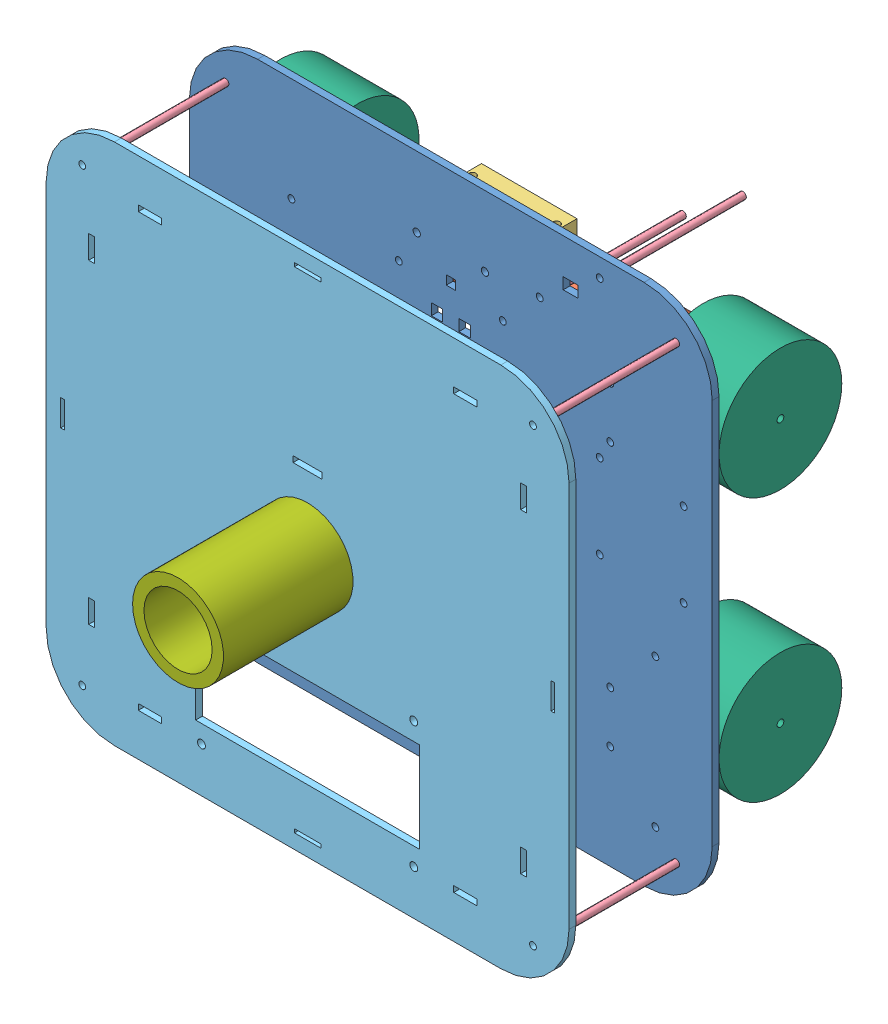
SolidWorks assembly Ensamblaje3.0, configuration Predeterminado. Lengths in mm.
Overall size (230 230 183).
20 component instances, 7 part files, 35 mates.
Components (placement in the parent):
- Basemenor 4.1-1: Basemenor 4.1 [Predeterminado] at (0.6616 -5.6238 228.5) size (230 230 3)
- Portamotores 3.1-1: Portamotores 3.1 [Predeterminado] at (-72.8434 52.3762 227.25) x (0 1 0) z (1 0 0) size (30 47 56.5)
- Portamotores 3.1-2: Portamotores 3.1 [Predeterminado] at (74.1666 -63.6238 227.25) x (0 -1 0) z (-1 0 0) size (30 47 56.5)
- Portamotores 3.1-3: Portamotores 3.1 [Predeterminado] at (74.1666 52.3762 227.25) x (0 -1 0) z (-1 0 0) size (30 47 56.5)
- Portamotores 3.1-4: Portamotores 3.1 [Predeterminado] at (-72.8434 -63.6238 227.25) x (0 1 0) z (1 0 0) size (30 47 56.5)
- Porta_sharp_1.0-1: Porta_sharp_1.0 [Predeterminado] at (-14.3384 78.3762 227.25) x (1 0 0) z (0 0 -1) size (42 12.16 31.5)
- Porta_sharp_1.0-2: Porta_sharp_1.0 [Predeterminado] at (49.6616 9.3762 227.25) x (0 -1 0) z (0 0 -1) size (42 12.16 31.5)
- Porta_sharp_1.0-3: Porta_sharp_1.0 [Predeterminado] at (-48.3384 -20.6238 227.25) x (0 1 0) z (0 0 -1) size (42 12.16 31.5)
- SIMULACION_TORNILLO_LARGO_M3-1: SIMULACION_TORNILLO_LARGO_M3 [Predeterminado] at (99.8038 -104.766 231.5) size (3 3 60)
- SIMULACION_TORNILLO_LARGO_M3-2: SIMULACION_TORNILLO_LARGO_M3 [Predeterminado] at (-98.4805 -104.766 231.5) size (3 3 60)
- SIMULACION_TORNILLO_LARGO_M3-3: SIMULACION_TORNILLO_LARGO_M3 [Predeterminado] at (99.8038 93.5183 231.5) size (3 3 60)
- SIMULACION_TORNILLO_LARGO_M3-4: SIMULACION_TORNILLO_LARGO_M3 [Predeterminado] at (-98.4805 93.5183 231.5) size (3 3 60)
- Basemayor_4.0-1: Basemayor_4.0 [Predeterminado] at (0.6616 -5.6238 291.5) size (230 230 3)
- SIMULACION_MECANUM-1: SIMULACION_MECANUM [Predeterminado] at (110.6666 -63.6238 196.5) x (0 0 1) z (-1 0 0) size (54 54 34)
- SIMULACION_MECANUM-2: SIMULACION_MECANUM [Predeterminado] at (-109.3434 -63.6238 196.5) x (0 0 -1) z (1 0 0) size (54 54 34)
- SIMULACION_MECANUM-3: SIMULACION_MECANUM [Predeterminado] at (-109.3434 52.3762 196.5) x (0 0 -1) z (1 0 0) size (54 54 34)
- SIMULACION_MECANUM-4: SIMULACION_MECANUM [Predeterminado] at (110.6666 52.3762 196.5) x (0 0 1) z (-1 0 0) size (54 54 34)
- SIMULACION_CILINDRO-1: SIMULACION_CILINDRO [Predeterminado] at (0.6616 -5.6238 231.5) size (40 40 120)
- SIMULACION_TORNILLO_LARGO_M3-5: SIMULACION_TORNILLO_LARGO_M3 [Predeterminado] at (39.7573 80.6908 168.5) size (3 3 60)
- SIMULACION_TORNILLO_LARGO_M3-6: SIMULACION_TORNILLO_LARGO_M3 [Predeterminado] at (66.1692 101.2428 168.5) size (3 3 60)
Mates (geometry in assembly coordinates):
- Coincidente1: coincident aligned: circle of Basemenor 4.1-1; circle of Porta_sharp_1.0-3
- Coincidente2: coincident anti-aligned: circle of Basemenor 4.1-1; circle of Porta_sharp_1.0-3
- Concéntrica5: concentric aligned: circle of Basemenor 4.1-1; circle of Portamotores 3.1-1
- Concéntrica6: concentric aligned: circle of Basemenor 4.1-1; circle of Portamotores 3.1-1
- Concéntrica7: concentric aligned: circle of Basemenor 4.1-1; circle of Portamotores 3.1-3
- Concéntrica8: concentric aligned: circle of Basemenor 4.1-1; circle of Portamotores 3.1-3
- Coincidente4: coincident anti-aligned: plane of Basemenor 4.1-1 through (0.6616 -5.6238 228.5) normal (0 0 -1); plane of Portamotores 3.1-3 through (20.1666 37.3762 228.5) normal (0 0 1)
- Coincidente5: coincident anti-aligned: plane of Basemenor 4.1-1 through (0.6616 -5.6238 228.5) normal (0 0 -1); plane of Portamotores 3.1-1 through (-18.8434 67.3762 228.5) normal (0 0 1)
- Concéntrica12: concentric aligned: circle of Basemenor 4.1-1; circle of Portamotores 3.1-2
- Concéntrica13: concentric aligned: circle of Basemenor 4.1-1; circle of Portamotores 3.1-2
- Coincidente6: coincident anti-aligned: plane of Basemenor 4.1-1 through (0.6616 -5.6238 228.5) normal (0 0 -1); plane of Portamotores 3.1-2 through (20.1666 -78.6238 228.5) normal (0 0 1)
- Concéntrica14: concentric aligned: circle of Basemenor 4.1-1; circle of Portamotores 3.1-4
- Concéntrica15: concentric aligned: circle of Basemenor 4.1-1; circle of Portamotores 3.1-4
- Coincidente7: coincident anti-aligned: plane of Basemenor 4.1-1 through (0.6616 -5.6238 228.5) normal (0 0 -1); plane of Portamotores 3.1-4 through (-18.8434 -48.6238 228.5) normal (0 0 1)
- Coincidente8: coincident aligned: circle of Basemenor 4.1-1; circle of Porta_sharp_1.0-1
- Coincidente9: coincident anti-aligned: circle of Basemenor 4.1-1; circle of Porta_sharp_1.0-1
- Coincidente10: coincident anti-aligned: circle of Basemenor 4.1-1; circle of Porta_sharp_1.0-2
- Coincidente11: coincident aligned: circle of Basemenor 4.1-1; circle of Porta_sharp_1.0-2
- Coincidente12: coincident aligned: circle of Basemenor 4.1-1; circle of SIMULACION_TORNILLO_LARGO_M3-3
- Coincidente13: coincident aligned: circle of Basemenor 4.1-1; circle of SIMULACION_TORNILLO_LARGO_M3-4
- Coincidente14: coincident aligned: circle of Basemenor 4.1-1; circle of SIMULACION_TORNILLO_LARGO_M3-2
- Coincidente15: coincident aligned: circle of Basemenor 4.1-1; circle of SIMULACION_TORNILLO_LARGO_M3-1
- Coincidente16: coincident aligned: circle of SIMULACION_TORNILLO_LARGO_M3-4; circle of Basemayor_4.0-1
- Concéntrica16: concentric anti-aligned: circle of Portamotores 3.1-3; circle of SIMULACION_MECANUM-4
- Coincidente17: coincident anti-aligned: plane of Portamotores 3.1-3 through (76.6666 52.3762 196.5) normal (1 0 0); plane of SIMULACION_MECANUM-4 through (76.6666 52.3762 196.5) normal (-1 0 0)
- Concéntrica17: concentric anti-aligned: circle of Portamotores 3.1-2; circle of SIMULACION_MECANUM-1
- Coincidente18: coincident anti-aligned: plane of Portamotores 3.1-2 through (76.6666 -63.6238 196.5) normal (1 0 0); plane of SIMULACION_MECANUM-1 through (76.6666 -63.6238 196.5) normal (-1 0 0)
- Concéntrica18: concentric anti-aligned: circle of Portamotores 3.1-1; circle of SIMULACION_MECANUM-3
- Coincidente19: coincident anti-aligned: plane of Portamotores 3.1-1 through (-75.3434 52.3762 196.5) normal (-1 0 0); plane of SIMULACION_MECANUM-3 through (-75.3434 52.3762 196.5) normal (1 0 0)
- Concéntrica19: concentric anti-aligned: circle of Portamotores 3.1-4; circle of SIMULACION_MECANUM-2
- Coincidente20: coincident anti-aligned: plane of Portamotores 3.1-4 through (-75.3434 -63.6238 196.5) normal (-1 0 0); plane of SIMULACION_MECANUM-2 through (-75.3434 -63.6238 196.5) normal (1 0 0)
- Coincidente22: coincident anti-aligned: circle of Basemayor_4.0-1; cylinder of SIMULACION_CILINDRO-1 through (0.6616 -5.6238 351.5) axis (0 0 -1) radius 20
- Coincidente23: coincident anti-aligned: plane of Basemenor 4.1-1 through (0.6616 -5.6238 231.5) normal (0 0 1); plane of SIMULACION_CILINDRO-1 through (0.6616 -5.6238 231.5) normal (0 0 -1)
- Coincidente24: coincident aligned: circle of Basemenor 4.1-1; circle of SIMULACION_TORNILLO_LARGO_M3-5
- Coincidente25: coincident aligned: circle of Basemenor 4.1-1; circle of SIMULACION_TORNILLO_LARGO_M3-6
